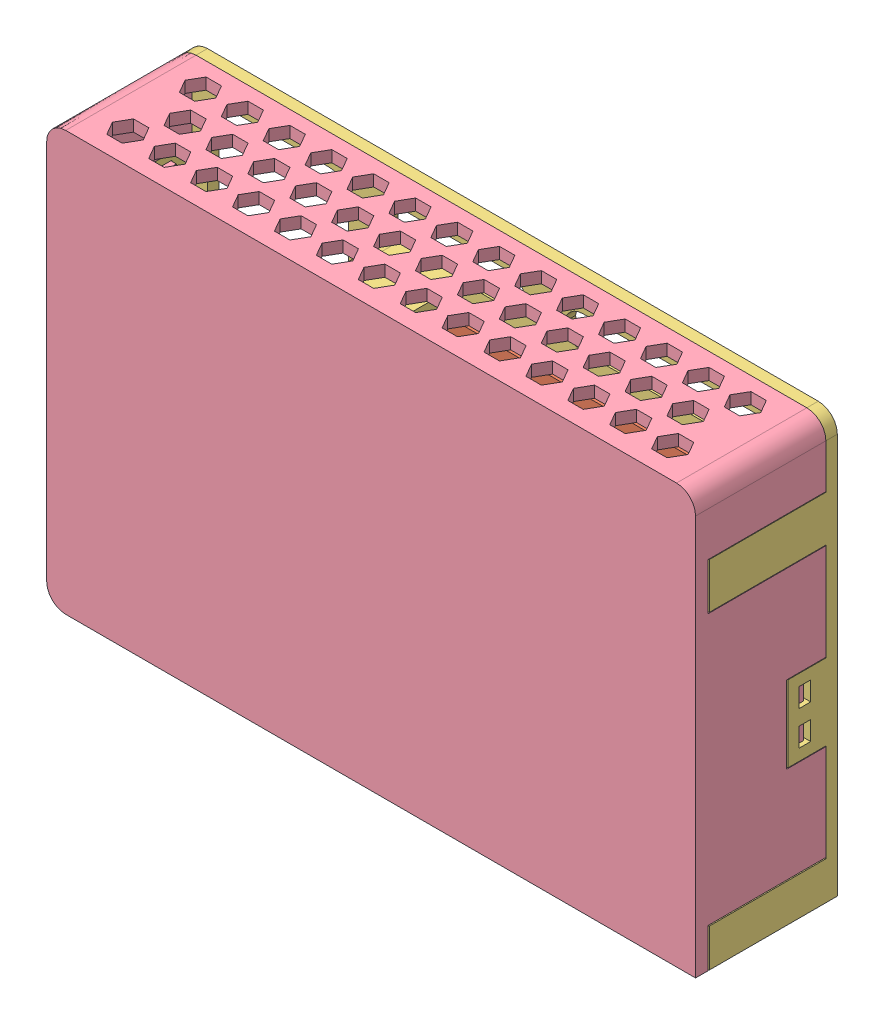
SolidWorks assembly garHAge_v2, configuration Default. Lengths in mm.
Overall size (170.3 110 37.2).
4 component instances, 4 part files, 9 mates.
Components (placement in the parent):
- pcb-1: pcb [Default] at (-123.4876 139.5702 63.2539) size (101 79.6 18.99)
- pcb_mount-1: pcb_mount [Default] at (-3.9876 20.0702 56.2539) size (112 90 27)
- wall_mount_on_junction_box_2gang-1: wall_mount_on_junction_box_2gang [Default] at (106.3124 14.4702 56.2539) x (-1 0 0) z (0 0 -1) size (170.3 110 33.6)
- cover-1: cover [Default] at (106.3124 124.4702 90.4539) x (-1 0 0) z (0 0 -1) size (170.3 110 34.2)
Mates (geometry in assembly coordinates):
- Coincident1: coincident anti-aligned: plane of pcb-1 through (47.0124 60.0702 63.2539) normal (0 0 -1); plane of pcb_mount-1 through (-3.9876 20.0702 63.2539) normal (0 0 1)
- Concentric1: concentric anti-aligned: circle of pcb-1; circle of pcb_mount-1
- Concentric2: concentric anti-aligned: circle of pcb-1; circle of pcb_mount-1
- Coincident2: coincident anti-aligned: plane of pcb_mount-1 through (-3.9876 20.0702 56.2539) normal (0 0 -1); plane of wall_mount_on_junction_box_2gang-1 through (106.3124 14.4702 56.2539) normal (0 0 1)
- Coincident5: coincident anti-aligned: plane of pcb_mount-1 through (-8.9876 105.0702 83.2539) normal (0 1 0); plane of wall_mount_on_junction_box_2gang-1 through (-8.9876 105.0702 83.8539) normal (0 -1 0)
- Coincident6: coincident anti-aligned: plane of pcb_mount-1 through (-8.9876 95.0702 83.2539) normal (-1 0 0); plane of wall_mount_on_junction_box_2gang-1 through (-8.9876 97.7702 53.2539) normal (1 0 0)
- Coincident7: coincident anti-aligned: plane of wall_mount_on_junction_box_2gang-1 through (106.3124 14.4702 56.2539) normal (0 0 1); plane of cover-1 through (106.3124 124.4702 56.2539) normal (0 0 -1)
- Coincident8: coincident aligned: plane of wall_mount_on_junction_box_2gang-1 through (-63.9876 14.4702 53.2539) normal (-1 0 0); plane of cover-1 through (-63.9876 124.4702 56.2539) normal (-1 0 0)
- Coincident9: coincident aligned: plane of wall_mount_on_junction_box_2gang-1 through (106.3124 124.4702 53.2539) normal (0 1 0); plane of cover-1 through (106.3124 124.4702 56.2539) normal (0 1 0)
